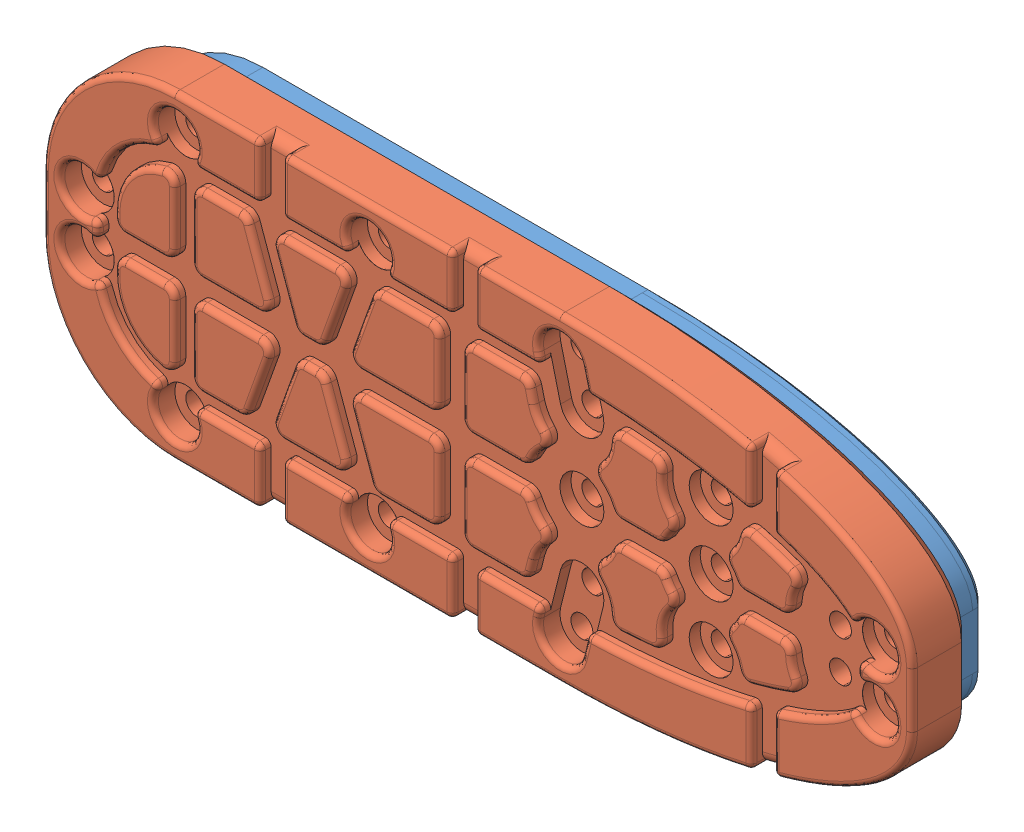
SolidWorks assembly 脚底包胶装配体, configuration 默认. Lengths in mm.
Overall size (159.99 63.94 18.11).
2 component instances, 2 part files, 5 mates.
Components (placement in the parent):
- 脚底板-1: 脚底板 [默认] at origin size (150.3 50.4 10.3)
- 橡胶脚底-1: 橡胶脚底 [默认] at (0 0 8) size (159.99 63.94 16.1)
Mates (geometry in assembly coordinates):
- 重合1: coordinate: point of 脚底板-1
- 在位1: in place: plane of 脚底板-1 through (0 0 8) normal (0 0 1); plane of 橡胶脚底-1 through (0 0 8) normal (0 0 1); moOrthogonalPlaneRef_w of 脚底板-1 through (0 0 8) normal (0 0 1); plane of 橡胶脚底-1 through (0 0 8) normal (0 1 0); plane of 脚底板-1 through (0 0 8) normal (0 0 1); plane of 橡胶脚底-1 through (0 0 8) normal (1 0 0); plane of 脚底板-1 through (0 0 8) normal (0 0 1); unknown of 橡胶脚底-1
- 重合2: coincident aligned: plane of 脚底板-1; plane of 橡胶脚底-1
- 重合3: coincident aligned: moOrthogonalPlaneRef_w of 脚底板-1 through (0 0 8) normal (0 1 0); plane of 橡胶脚底-1 through (0 0 8) normal (0 1 0)
- 重合4: coincident anti-aligned: moOrthogonalPlaneRef_w of 脚底板-1 through (0 0 8) normal (-1 0 0); plane of 橡胶脚底-1 through (0 0 8) normal (1 0 0)
